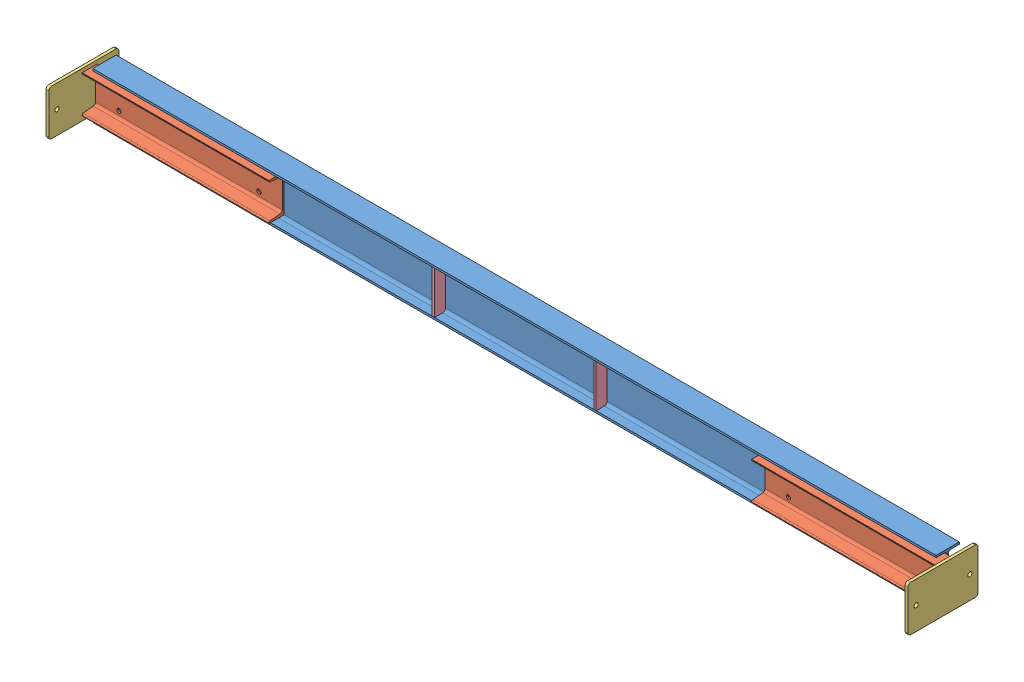
SolidWorks assembly Assemblage poutre extrémitée, configuration Default. Lengths in mm.
Overall size (3692 200 300).
9 component instances, 4 part files, 25 mates.
Components (placement in the parent):
- IPE-1: IPE [Default<Brut d'usinage>] at origin size (3612 200 100)
- UPN de fixation-1: UPN de fixation [avec trou cylindre<Brut de soudage>] at (-1434 -20.5 35.3) x (1 0 0) z (0 -1 0) size (800 65 160)
- Platine de fixation-1: Platine de fixation [Default] at (-1834 -102.5 60.3) x (0 0 -1) z (1 0 0) size (300 195 12)
- UPN de fixation-2: UPN de fixation [avec trou cylindre<Brut d'usinage>] at (1434 -20.5 35.3) x (1 0 0) z (0 -1 0) size (800 65 160)
- Platine de fixation-2: Platine de fixation [Default] at (1846 -102.5 60.3) x (0 0 -1) z (1 0 0) size (300 195 12)
- Renfort IPE-1: Renfort IPE [Default] at (-352 -8.5 50) x (0 0 1) z (-1 0 0) size (47.2 183 10)
- Renfort IPE-2: Renfort IPE [Default] at (340 -8.5 50) x (0 0 1) z (-1 0 0) size (47.2 183 10)
- Renfort IPE-5: Renfort IPE [Default] at (-352 -191.5 -50) x (0 0 -1) z (-1 0 0) size (47.2 183 10)
- Renfort IPE-6: Renfort IPE [Default] at (340 -191.5 -50) x (0 0 -1) z (-1 0 0) size (47.2 183 10)
Mates (geometry in assembly coordinates):
- Coïncidente8: coincident anti-aligned: plane of IPE-1 through (1806 -179.5 2.8) normal (0 0 1); plane of UPN de fixation-1 through (-1034 -20.5 2.8) normal (0 0 -1)
- Coïncidente9: coincident aligned: line of IPE-1 through (1806 -20.5 2.8) axis (-1 0 0); line of UPN de fixation-1 through (-1034 -20.5 2.8) axis (-1 0 0)
- Distance5: distance = 28 mm aligned: plane of UPN de fixation-1 through (-1834 -22.7768 62.3) normal (-1 0 0); plane of IPE-1 through (-1806 -179.5 14.8) normal (-1 0 0)
- Distance6: distance = 5 mm aligned: plane of IPE-1 through (1806 0 50) normal (0 1 0); plane of Platine de fixation-1 through (-1846 -5 210.3) normal (0 1 0)
- Coïncidente14: coincident anti-aligned: plane of IPE-1 through (1806 -179.5 2.8) normal (0 0 1); plane of UPN de fixation-2 through (1834 -20.5 2.8) normal (0 0 -1)
- Coïncidente15: coincident aligned: line of IPE-1 through (1806 -20.5 2.8) axis (-1 0 0); line of UPN de fixation-2 through (1834 -20.5 2.8) axis (-1 0 0)
- Distance8: distance = 28 mm aligned: plane of UPN de fixation-2 through (1834 -22.7768 62.3) normal (1 0 0); plane of IPE-1 through (1806 -179.5 14.8) normal (1 0 0)
- Distance9: distance = 5 mm aligned: plane of Platine de fixation-2 through (1834 -5 210.3) normal (0 1 0); plane of IPE-1 through (1806 0 50) normal (0 1 0)
- Coïncidente11: coincident anti-aligned: plane of UPN de fixation-1 through (-1834 -22.7768 62.3) normal (-1 0 0); plane of Platine de fixation-1 through (-1834 -102.5 60.3) normal (1 0 0)
- Distance7: distance = 200 mm aligned: plane of Platine de fixation-1 through (-1846 -200 210.3) normal (0 0 1); plane of UPN de fixation-1 through (-1034 -158 10.3) normal (0 0 1)
- Coïncidente18: coincident aligned: plane of Platine de fixation-1 through (-1846 -200 210.3) normal (0 0 1); plane of Platine de fixation-2 through (1834 -200 210.3) normal (0 0 1)
- Coïncidente16: coincident anti-aligned: plane of UPN de fixation-2 through (1834 -22.7768 62.3) normal (1 0 0); plane of Platine de fixation-2 through (1834 -102.5 60.3) normal (-1 0 0)
- Coïncidente19: coordinate: point of IPE-1; point of assembly
- Coïncidente20: coincident anti-aligned: plane of IPE-1 through (1806 -179.5 2.8) normal (0 0 1); plane of Renfort IPE-1 through (-342 -179.5 2.8) normal (0 0 -1)
- Coïncidente21: coincident anti-aligned: plane of IPE-1 through (1806 -8.5 14.8) normal (0 -1 0); plane of Renfort IPE-1 through (-342 -8.5 14.8) normal (0 1 0)
- Distance10: distance = 682 mm anti-aligned: plane of Renfort IPE-1 through (-352 -20.5 14.8) normal (-1 0 0); plane of UPN de fixation-1 through (-1034 -22.7768 62.3) normal (1 0 0)
- Coïncidente23: coincident anti-aligned: plane of IPE-1 through (1806 -179.5 2.8) normal (0 0 1); plane of Renfort IPE-2 through (350 -179.5 2.8) normal (0 0 -1)
- Coïncidente24: coincident anti-aligned: plane of IPE-1 through (1806 -8.5 14.8) normal (0 -1 0); plane of Renfort IPE-2 through (350 -8.5 14.8) normal (0 1 0)
- Distance11: distance = 682 mm anti-aligned: plane of Renfort IPE-2 through (340 -20.5 14.8) normal (-1 0 0); plane of Renfort IPE-1 through (-342 -20.5 14.8) normal (1 0 0)
- Coïncidente29: coincident anti-aligned: plane of IPE-1 through (1806 -20.5 -2.8) normal (0 0 -1); plane of Renfort IPE-5 through (-342 -20.5 -2.8) normal (0 0 1)
- Coïncidente30: coincident anti-aligned: plane of IPE-1 through (1806 -8.5 -50) normal (0 -1 0); plane of Renfort IPE-5 through (-342 -8.5 -50) normal (0 1 0)
- Coïncidente31: coincident aligned: plane of Renfort IPE-1 through (-352 -20.5 14.8) normal (-1 0 0); plane of Renfort IPE-5 through (-352 -179.5 -14.8) normal (-1 0 0)
- Coïncidente32: coincident anti-aligned: plane of IPE-1 through (1806 -20.5 -2.8) normal (0 0 -1); plane of Renfort IPE-6 through (350 -20.5 -2.8) normal (0 0 1)
- Coïncidente33: coincident anti-aligned: plane of IPE-1 through (1806 -8.5 -50) normal (0 -1 0); plane of Renfort IPE-6 through (350 -8.5 -50) normal (0 1 0)
- Coïncidente34: coincident aligned: plane of Renfort IPE-2 through (340 -20.5 14.8) normal (-1 0 0); plane of Renfort IPE-6 through (340 -179.5 -14.8) normal (-1 0 0)
